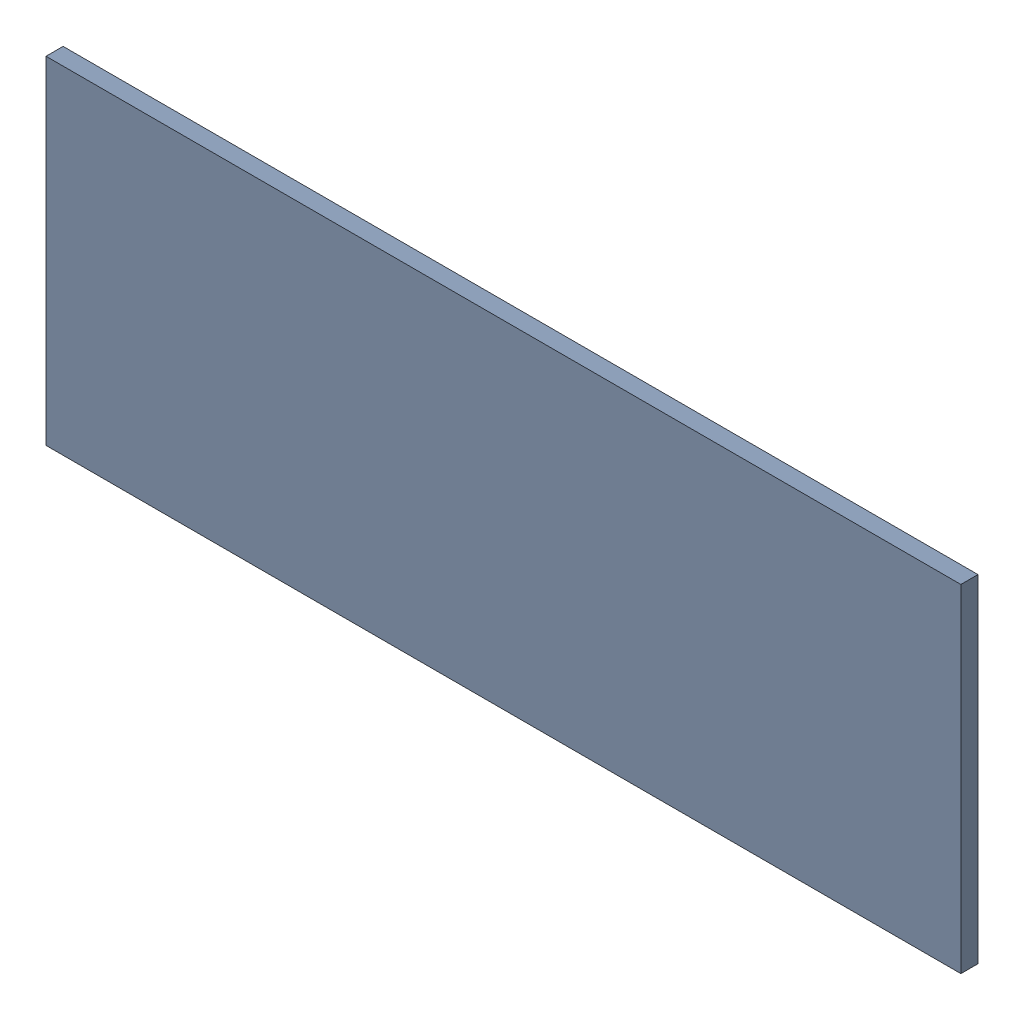
SolidWorks assembly Pad RAK4600-2(14.5mm,26.25mm) on Top Layer, configuration Predeterminado. Lengths in mm.
Overall size (1.9 0.7 0.04).
2 component instances, 1 part files, 0 mates.
Components (placement in the parent):
- Pad RAK4600-2(14.5mm,26.25mm) on Top Layer-1-1: Pad RAK4600-2(14.5mm,26.25mm) on Top Layer-1 [Predeterminado] at (-68.317 -44.187 -0.0457) size (1.9 0.7 0.04)
  - Pad RAK4600-2(14.5mm,26.25mm) on Top Layer-Part-1-1: Pad RAK4600-2(14.5mm,26.25mm) on Top Layer-Part-1 [Predeterminado] at origin size (1.9 0.7 0.04)
